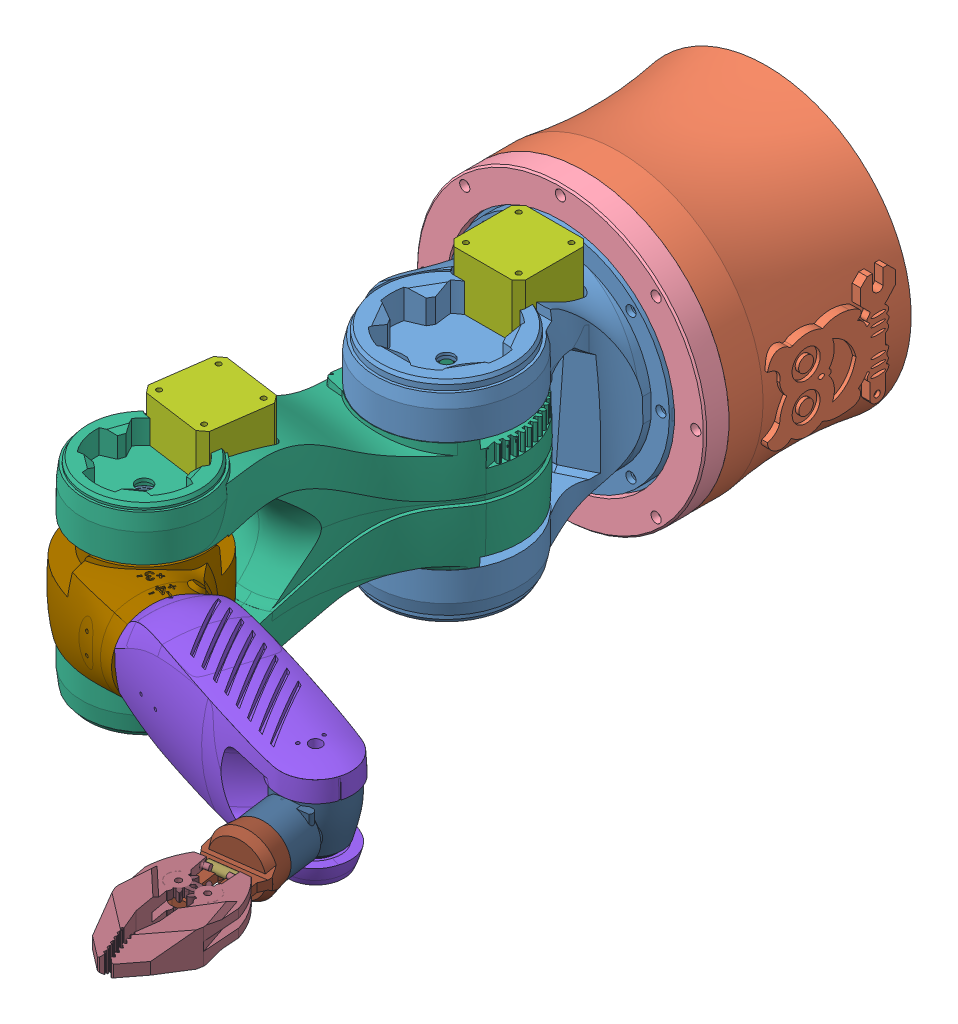
SolidWorks assembly Robot Arm New, configuration Domyślna. Lengths in mm.
Overall size (290.3 170 572.34).
57 component instances, 15 part files, 56 mates.
Components (placement in the parent):
- Base-1: Base [Domyślna] at (0 0 -274.858) size (145 145 134.73)
- Support-1: Support [Domyślna] at origin size (170 170 107)
- Ball-1: Ball [Default] at (-49.328 -3.3193 1.5741) x (0.766361 0.399042 0.503444) z (-0.305296 0.915757 -0.26112) size (8 8 8)
- Ring-1: Ring [Domyślna] at (3.9829 0 -274.858) x (0 0 -1) z (1 0 0) size (14.01 170 170)
- Nema 17 x 33-1: Nema 17 x 33 [Default] at (42.1555 0 -16.75) x (0 -1 0) z (0 0 -1) size (42 42 56.05) (hidden)
- Small Gear-1: Small Gear [Default] at (42.1555 0 0) x (0.815821 -0.578304 0) z (0 0 1) size (13.1 13.1 6.3)
- arm-1: arm [Całe ramię] at (58.3865 3.8108 -373.6901) x (0.990544 0 0.137198) z (-0.137198 0 0.990544) size (92.9 119.57 238.58)
- Nema 17 x 33-2: Nema 17 x 33 [Default] at (10.2329 42 42.8) x (0 0 1) z (0 1 0) size (42 42 56.05)
- arm3-1: arm3 [Domyślna] at (70.0108 0 -494.6882) x (0.958155 0 0.28625) z (-0.28625 0 0.958155) size (152.17 73.81 55.12)
- arm2-1: arm2 [Domyślna] at (169.458 1.3469 -451.9696) x (0.958155 0 0.28625) z (-0.28625 0 0.958155) size (97.18 73.94 92.73)
- arm5-1: arm5 [Domyślna] at (648.9164 0 1000.8949) x (-0.991316 0 0.131504) z (-0.131504 0 -0.991316) size (40.21 35.25 58.35)
- Grasper Assembly-1: Grasper Assembly [Default] at (171.8003 0.9567 369.8305) x (-0.991316 0 0.131504) z (-0.131504 0 -0.991316) size (51.49 36 114.44)
  - Grasper Body-1: Grasper Body [Default] at (0 0 18.5286) size (37.45 36 58.53)
  - Spring-1: Spring [Default] at (0 2.9735 -8.6) x (1 0 0) z (0 -0.96148 0.274876) size (18 5.2 5.2)
  - Grasper-8: Grasper [Domyślna] at (7.6 0 -30) x (0.060502 0 0.998168) z (0 1 0) size (80.6 25.49 20)
  - Grasper-9: Grasper [Domyślna] at (-7.6 0 -30) x (-0.060502 0 0.998168) z (0 -1 0) size (80.6 25.49 20)
- Nema 17 x 33-3: Nema 17 x 33 [Default] at (-6.0764 38.9282 206.9971) x (-0.137198 0 0.990544) z (0 1 0) size (42 42 56.05)
- Small Gear-3: Small Gear [Default] at (-6.0764 22.1782 206.9971) x (0.815821 0 -0.578304) z (0 -1 0) size (13.1 13.1 6.3)
- Nema 17 x 33-4: Nema 17 x 33 [Default] at (42.1555 0 -15.45) x (0 -1 0) z (0 0 -1) size (42 42 56.05)
- Ball-2: Ball [Default] at (-47.4592 -13.6366 1.5741) x (0.673787 0.540885 0.503444) z (-0.478085 0.838601 -0.26112) size (8 8 8)
- Ball-3: Ball [Default] at (-43.6135 -23.391 1.5741) x (0.555319 0.661941 0.503444) z (-0.632501 0.729218 -0.26112) size (8 8 8)
- Ball-4: Ball [Default] at (-37.9387 -32.2078 1.5741) x (0.41551 0.757559 0.503444) z (-0.762611 0.591811 -0.26112) size (8 8 8)
- Ball-5: Ball [Default] at (-30.6528 -39.748 1.5741) x (0.259734 0.824065 0.503444) z (-0.863415 0.431661 -0.26112) size (8 8 8)
- Ball-6: Ball [Default] at (-22.036 -45.7219 1.5741) x (0.093976 0.858902 0.503444) z (-0.931037 0.254923 -0.26112) size (8 8 8)
- Ball-7: Ball [Default] at (-12.4192 -49.9 1.5741) x (-0.075393 0.860732 0.503444) z (-0.962881 0.068389 -0.26112) size (8 8 8)
- Ball-8: Ball [Default] at (-2.1722 -52.1217 1.5741) x (-0.241865 0.829485 0.503444) z (-0.957721 -0.120774 -0.26112) size (8 8 8)
- Ball-9: Ball [Default] at (8.3115 -52.3016 1.5741) x (-0.399042 0.766361 0.503444) z (-0.915757 -0.305296 -0.26112) size (8 8 8)
- Ball-10: Ball [Default] at (18.6287 -50.4328 1.5741) x (-0.540885 0.673787 0.503444) z (-0.838601 -0.478085 -0.26112) size (8 8 8)
- Ball-11: Ball [Default] at (28.3832 -46.5871 1.5741) x (-0.661941 0.555319 0.503444) z (-0.729218 -0.632501 -0.26112) size (8 8 8)
- Ball-12: Ball [Default] at (37.1999 -40.9123 1.5741) x (-0.757559 0.41551 0.503444) z (-0.591811 -0.762611 -0.26112) size (8 8 8)
- Ball-13: Ball [Default] at (44.7401 -33.6264 1.5741) x (-0.824065 0.259734 0.503444) z (-0.431661 -0.863415 -0.26112) size (8 8 8)
- Ball-14: Ball [Default] at (50.7141 -25.0096 1.5741) x (-0.858902 0.093976 0.503444) z (-0.254923 -0.931037 -0.26112) size (8 8 8)
- Ball-15: Ball [Default] at (54.8922 -15.3928 1.5741) x (-0.860732 -0.075393 0.503444) z (-0.068389 -0.962881 -0.26112) size (8 8 8)
- Ball-16: Ball [Default] at (57.1139 -5.1457 1.5741) x (-0.829485 -0.241865 0.503444) z (0.120774 -0.957721 -0.26112) size (8 8 8)
- Ball-17: Ball [Default] at (57.2937 5.3379 1.5741) x (-0.766361 -0.399042 0.503444) z (0.305296 -0.915757 -0.26112) size (8 8 8)
- Ball-18: Ball [Default] at (55.4249 15.6551 1.5741) x (-0.673787 -0.540885 0.503444) z (0.478085 -0.838601 -0.26112) size (8 8 8)
- Ball-19: Ball [Default] at (51.5792 25.4096 1.5741) x (-0.555319 -0.661941 0.503444) z (0.632501 -0.729218 -0.26112) size (8 8 8)
- Ball-20: Ball [Default] at (45.9044 34.2263 1.5741) x (-0.41551 -0.757559 0.503444) z (0.762611 -0.591811 -0.26112) size (8 8 8)
- Ball-21: Ball [Default] at (38.6186 41.7665 1.5741) x (-0.259734 -0.824065 0.503444) z (0.863415 -0.431661 -0.26112) size (8 8 8)
- Ball-22: Ball [Default] at (30.0017 47.7405 1.5741) x (-0.093976 -0.858902 0.503444) z (0.931037 -0.254923 -0.26112) size (8 8 8)
- Ball-23: Ball [Default] at (20.385 51.9186 1.5741) x (0.075393 -0.860732 0.503444) z (0.962881 -0.068389 -0.26112) size (8 8 8)
- Ball-24: Ball [Default] at (10.1379 54.1403 1.5741) x (0.241865 -0.829485 0.503444) z (0.957721 0.120774 -0.26112) size (8 8 8)
- Ball-25: Ball [Default] at (-0.3457 54.3202 1.5741) x (0.399042 -0.766361 0.503444) z (0.915757 0.305296 -0.26112) size (8 8 8)
- Ball-26: Ball [Default] at (-10.663 52.4513 1.5741) x (0.540885 -0.673787 0.503444) z (0.838601 0.478085 -0.26112) size (8 8 8)
- Ball-27: Ball [Default] at (-20.4174 48.6056 1.5741) x (0.661941 -0.555319 0.503444) z (0.729218 0.632501 -0.26112) size (8 8 8)
- Ball-28: Ball [Default] at (-29.2342 42.9308 1.5741) x (0.757559 -0.41551 0.503444) z (0.591811 0.762611 -0.26112) size (8 8 8)
- Ball-29: Ball [Default] at (-36.7744 35.645 1.5741) x (0.824065 -0.259734 0.503444) z (0.431661 0.863415 -0.26112) size (8 8 8)
- Ball-30: Ball [Default] at (-42.7484 27.0281 1.5741) x (0.858902 -0.093976 0.503444) z (0.254923 0.931037 -0.26112) size (8 8 8)
- Ball-31: Ball [Default] at (-46.9265 17.4114 1.5741) x (0.860732 0.075393 0.503444) z (0.068389 0.962881 -0.26112) size (8 8 8)
- Ball-32: Ball [Default] at (-49.1481 7.1643 1.5741) x (0.829485 0.241865 0.503444) z (-0.120774 0.957721 -0.26112) size (8 8 8)
- Bearing 608-1: Bearing 608 [Domyślna] at (16.4829 -33.2407 91.5) x (1 0 0) z (0 1 0) size (22 22 7)
- Bearing 608-2: Bearing 608 [Domyślna] at (16.4829 31.5 91.5) x (0.837169 0 0.546944) z (0 -1 0) size (22 22 7)
- Shaft 8x80-1: Shaft 8x80 [Domyślna] at (16.4829 1.2593 91.5) x (0.98903 0 0.147715) z (0 -1 0) size (8 8 80)
- Bearing 608-3: Bearing 608 [Domyślna] at (-5.1258 -31.7407 247.5106) x (1 0 0.000468) z (0 1 0) size (22 22 7)
- Bearing 608-4: Bearing 608 [Domyślna] at (-5.1258 35.0093 247.5106) x (0.425392 0 0.905009) z (0 -1 0) size (22 22 7)
- Shaft 8x80-2: Shaft 8x80 [Domyślna] at (-5.1258 1.7593 247.5106) x (0.411131 0 -0.911576) z (0 1 0) size (8 8 80)
- Small Gear-4: Small Gear [Default] at (10.2329 25.25 42.8) x (0.815821 0 -0.578304) z (0 -1 0) size (13.1 13.1 6.3)
Mates (geometry in assembly coordinates):
- Wspólnie2: coincident anti-aligned: plane of Base-1 through (3.9829 1.0093 0) normal (0 0 -1); plane of assembly through (0 0 0) normal (0 0 1)
- Wspólnie3: coincident aligned: plane of Base-1 through (0 0 -274.858) normal (0 1 0); plane of assembly through (0 0 0) normal (0 1 0)
- Wspólnie4: coincident aligned: plane of Base-1 through (0 0 -274.858) normal (1 0 0); plane of assembly through (0 0 0) normal (1 0 0)
- Ustalone1: in place: plane of Support-1 through (0 0 0) normal (0 0 1); moOrthogonalPlaneRef_w of Support-1 through (0 0 0) normal (0 1 0); plane of Support-1 through (0 0 0) normal (1 0 0); unknown of Support-1
- Wspólnie5: coincident aligned: plane of Support-1; plane of assembly
- Wspólnie6: coincident aligned: plane of Support-1 through (0 0 0) normal (0 1 0); moOrthogonalPlaneRef_w of assembly
- Wspólnie7: coincident anti-aligned: plane of Support-1 through (0 0 0) normal (1 0 0); moOrthogonalPlaneRef_w of assembly
- Stycznie1: tangent: torus of Base-1; sphere of Ball-1
- Ustalone2: in place: plane of Base-1 through (3.9829 0 -274.858) normal (1 0 0); plane of Ring-1 through (3.9829 0 -274.858) normal (1 0 0); plane of Base-1 through (3.9829 0 -274.858) normal (1 0 0); line of Ring-1 through (0 -274.858 0) axis (1 0 0); plane of Base-1 through (3.9829 0 -274.858) normal (1 0 0); plane of Ring-1 through (3.9829 0 -274.858) normal (0 0 -1); plane of Base-1 through (3.9829 0 -274.858) normal (1 0 0); unknown of Ring-1
- Wspólnie8: coincident aligned: plane of Base-1; plane of Ring-1
- Wspólnie9: coincident aligned: moOrthogonalPlaneRef_w of Base-1 through (0 -274.858 0) axis (1 0 0); plane of Ring-1
- Wspólnie10: coincident anti-aligned: moOrthogonalPlaneRef_w of Base-1 through (0 -274.858 0) axis (0 1 0); plane of Ring-1 through (3.9829 0 -274.858) normal (0 0 -1)
- Koncentryczne1: concentric aligned: cylinder of Nema 17 x 33-1 through (42.1555 0 6.3) axis (0 0 -1) radius 2.5; cylinder of Small Gear-1 through (42.1555 0 6.3) axis (0 0 -1) radius 2.5
- Wspólnie11: coincident aligned: plane of Nema 17 x 33-1 through (42.1555 0 6.3) normal (0 0 1); plane of Small Gear-1 through (42.1555 0 6.3) normal (0 0 1)
- Wspólnie13: coincident aligned: plane of Base-1 through (3.9829 1.0093 0) normal (0 0 -1); plane of Small Gear-1 through (42.1555 0 0) normal (0 0 -1)
- Symetrycznie2: symmetric aligned: plane of Nema 17 x 33-1 through (63.1555 21 -49.75) normal (0 1 0); plane of Nema 17 x 33-1 through (63.1555 -21 -49.75) normal (0 -1 0); plane of assembly through (0 0 0) normal (0 1 0)
- Wspólnie20: coincident anti-aligned: plane of Base-1 through (16.4829 31.2593 91.5) normal (0 -1 0); plane of arm-1 through (16.4829 31.2593 91.5) normal (0 1 0)
- Koncentryczne4: concentric aligned: cylinder of Base-1 through (16.4829 -71.4907 91.5) axis (0 1 0) radius 4.5; cylinder of arm-1 through (16.4829 25.2593 91.5) axis (0 1 0) radius 34.25
- Wspólnie21: coincident anti-aligned: plane of Base-1 through (27.2329 42 25.3) normal (0 1 0); plane of Nema 17 x 33-2 through (10.2329 42 42.8) normal (0 -1 0)
- Wspólnie22: coincident anti-aligned: plane of Base-1 through (31.2329 42 59.8) normal (-1 0 0); plane of Nema 17 x 33-2 through (31.2329 75 21.8) normal (1 0 0)
- Wspólnie23: coincident anti-aligned: plane of Base-1 through (-7.2671 42 63.8) normal (0 0 -1); plane of Nema 17 x 33-2 through (-10.7671 75 63.8) normal (0 0 1)
- Wspólnie25: coincident anti-aligned: plane of arm3-1; plane of arm2-1
- Równolegle2: parallel aligned: plane of arm3-1; plane of arm2-1
- Koncentryczne9: concentric anti-aligned: cylinder of arm3-1 through (164.7282 1.7365 316.5189) axis (0 1 0) radius 14.5; cylinder of arm5-1 through (164.7282 -6.2933 316.5189) axis (0 -1 0) radius 14.5
- Wspólnie28: coincident aligned: plane of arm3-1; plane of arm5-1
- Równolegle3: parallel aligned: plane of ? through (7.9657 2.0185 -119) normal (0 0 -1); plane of arm5-1 through (354.231 0.8544 86.367) normal (0 0 -1)
- Koncentryczne12: concentric aligned: cylinder of arm5-1 through (169.7253 0.9567 354.1889) axis (0.131504 0 0.991316) radius 10; cylinder of Grasper Assembly-1/Grasper Body-1 through (168.7062 0.9567 346.5062) axis (0.131504 0 0.991316) radius 4
- Wspólnie34: coincident anti-aligned: plane of arm3-1; plane of arm2-1
- Koncentryczne13: concentric aligned: cylinder of arm-1 through (-6.0764 12.9282 206.9971) axis (0 1 0) radius 11.1; cylinder of Nema 17 x 33-3 through (-6.0764 15.8782 206.9971) axis (0 1 0) radius 2.5
- Koncentryczne14: concentric aligned: cylinder of arm-1 through (-23.5564 40.2593 220.224) axis (0 -1 0) radius 3; cylinder of Nema 17 x 33-3 through (-23.5564 71.9282 220.224) axis (0 -1 0) radius 1.5
- Wspólnie37: coincident aligned: plane of arm3-1; plane of assembly through (0 0 0) normal (0 1 0)
- Wspólnie38: coincident anti-aligned: plane of arm-1 through (8.6438 38.9282 226.4506) normal (0 1 0); plane of Nema 17 x 33-3 through (-6.0764 38.9282 206.9971) normal (0 -1 0)
- Koncentryczne18: concentric aligned: cylinder of Nema 17 x 33-3 through (-6.0764 15.8782 206.9971) axis (0 1 0) radius 2.5; cylinder of Small Gear-3 through (-6.0764 15.8782 206.9971) axis (0 1 0) radius 2.5
- Wspólnie41: coincident aligned: plane of Nema 17 x 33-3 through (-6.0764 15.8782 206.9971) normal (0 -1 0); plane of Small Gear-3 through (-6.0764 15.8782 206.9971) normal (0 -1 0)
- Wspólnie42: coincident anti-aligned: plane of Support-1 through (63.1555 17 42.0378) normal (-1 0 0); plane of Nema 17 x 33-4 through (63.1555 21 -48.45) normal (1 0 0)
- Koncentryczne19: concentric anti-aligned: cylinder of Support-1 through (26.6555 15.5 -2) axis (0 0 -1) radius 1.75; cylinder of Nema 17 x 33-4 through (26.6555 15.5 -48.45) axis (0 0 1) radius 1.5
- Wspólnie43: coincident anti-aligned: plane of Support-1 through (42.1555 0 -15.45) normal (0 0 -1); plane of Nema 17 x 33-4 through (42.1555 0 -15.45) normal (0 0 1)
- Koncentryczne20: concentric anti-aligned: cylinder of Base-1 through (16.4829 -38.7407 91.5) axis (0 1 0) radius 11.1; cylinder of Bearing 608-1 through (16.4829 -29.7407 91.5) axis (0 -1 0) radius 11
- Odległość4: distance = 2 mm anti-aligned: plane of Base-1 through (16.4829 -38.7407 91.5) normal (0 1 0); plane of Bearing 608-1 through (16.4829 -36.7407 91.5) normal (0 -1 0)
- Koncentryczne21: concentric aligned: cylinder of Base-1 through (16.4829 -38.7407 91.5) axis (0 1 0) radius 11.1; cylinder of Bearing 608-2 through (16.4829 28 91.5) axis (0 1 0) radius 11
- Odległość3: distance = 7 mm anti-aligned: plane of Base-1 through (16.4829 42 91.5) normal (0 -1 0); plane of Bearing 608-2 through (16.4829 35 91.5) normal (0 1 0)
- Koncentryczne22: concentric anti-aligned: cylinder of Bearing 608-1 through (16.4829 -29.7407 91.5) axis (0 -1 0) radius 4; cylinder of Shaft 8x80-1 through (16.4829 -38.7407 91.5) axis (0 1 0) radius 4
- Wspólnie47: coincident anti-aligned: plane of Base-1 through (16.4829 -38.7407 91.5) normal (0 1 0); plane of Shaft 8x80-1 through (16.4829 -38.7407 91.5) normal (0 -1 0)
- Koncentryczne23: concentric anti-aligned: cylinder of arm-1 through (-5.1258 -49.1892 247.5106) axis (0 1 0) radius 11.1; cylinder of Bearing 608-3 through (-5.1258 -28.2407 247.5106) axis (0 -1 0) radius 11
- Wspólnie48: coincident aligned: plane of arm-1 through (-5.1258 -28.2407 247.5106) normal (0 1 0); plane of Bearing 608-3 through (-5.1258 -28.2407 247.5106) normal (0 1 0)
- Koncentryczne24: concentric aligned: cylinder of arm-1 through (-5.1258 -49.1892 247.5106) axis (0 1 0) radius 11.1; cylinder of Bearing 608-4 through (-5.1258 31.5093 247.5106) axis (0 1 0) radius 11
- Wspólnie49: coincident aligned: plane of arm-1 through (-5.1258 31.5093 247.5106) normal (0 -1 0); plane of Bearing 608-4 through (-5.1258 31.5093 247.5106) normal (0 -1 0)
- Odległość5: distance = 3 mm aligned: plane of Shaft 8x80-2 through (-5.1258 -38.2407 247.5106) normal (0 -1 0); plane of Bearing 608-3 through (-5.1258 -35.2407 247.5106) normal (0 -1 0)
- Koncentryczne26: concentric aligned: cylinder of Nema 17 x 33-2 through (10.2329 18.95 42.8) axis (0 1 0) radius 2.5; cylinder of Small Gear-4 through (10.2329 18.95 42.8) axis (0 1 0) radius 2.5
- Wspólnie50: coincident aligned: plane of Nema 17 x 33-2 through (10.2329 18.95 42.8) normal (0 -1 0); plane of Small Gear-4 through (10.2329 18.95 42.8) normal (0 -1 0)
- Równolegle4: parallel anti-aligned: plane of Grasper Assembly-1/Grasper Body-1 through (169.3637 -1.5433 351.4628) normal (0 -1 0); plane of assembly through (0 0 0) normal (0 1 0)
- Koncentryczne27: concentric anti-aligned: cylinder of Bearing 608-4 through (-5.1258 31.5093 247.5106) axis (0 1 0) radius 4; cylinder of Shaft 8x80-2 through (-5.1258 41.7593 247.5106) axis (0 -1 0) radius 4
- Koncentryczne28: concentric aligned: cylinder of arm2-1 through (-5.1258 38.7071 247.5106) axis (0 -1 0) radius 4.1; cylinder of Shaft 8x80-2 through (-5.1258 41.7593 247.5106) axis (0 -1 0) radius 4
- Koncentryczne30: concentric aligned: cylinder of arm3-1 through (40.7104 1.7365 279.4685) axis (0.958155 0 0.28625) radius 22.55; cylinder of arm2-1 through (36.3354 1.7365 278.1615) axis (0.958155 0 0.28625) radius 22.5
- Wspólnie52: coincident anti-aligned: plane of arm3-1 through (41.1262 25.4865 279.5927) normal (-0.958155 0 -0.28625); plane of arm2-1 through (34.2848 1.7365 302.4926) normal (0.958155 0 0.28625)
- Coincident1: coincident anti-aligned: plane of arm5-1 through (169.7582 0.9567 354.4368) normal (0.131504 0 0.991316); plane of Grasper Assembly-1/Grasper Body-1 through (169.7582 0.9567 354.4368) normal (-0.131504 0 -0.991316)
